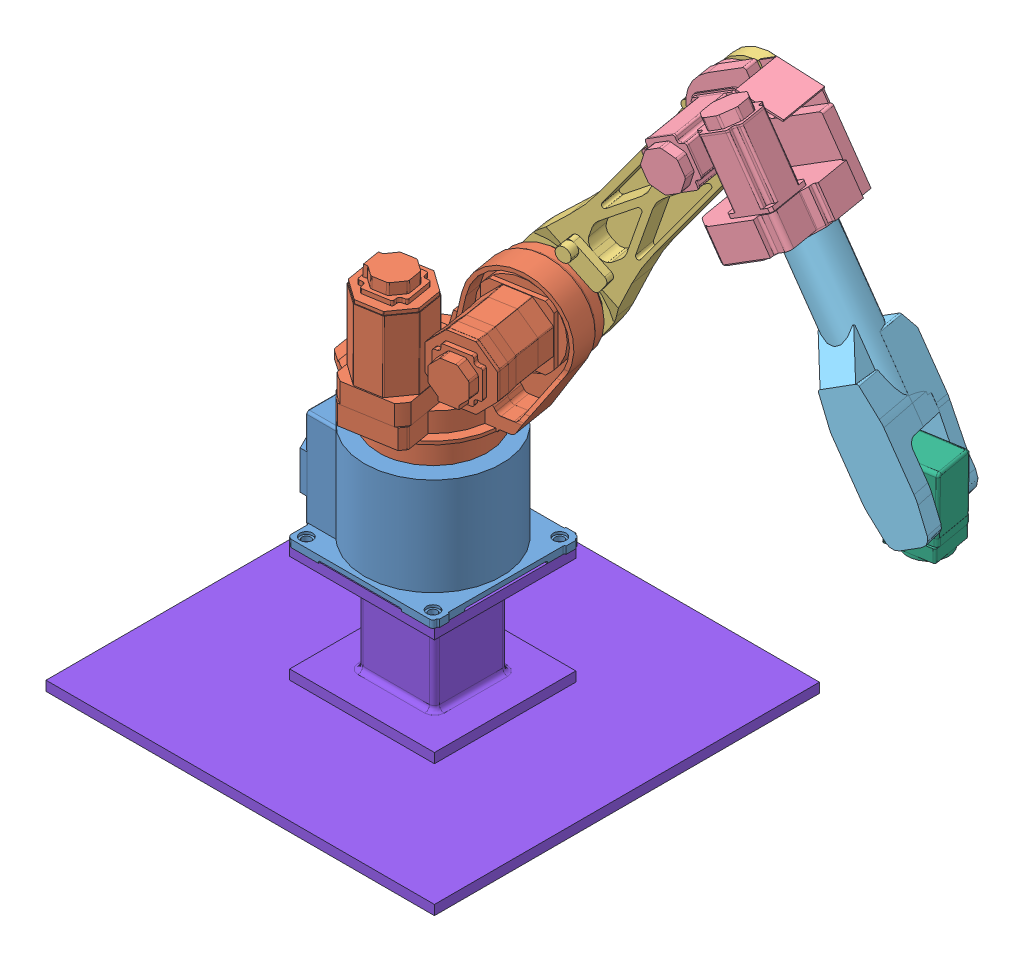
SolidWorks assembly M6iB, configuration Zero Position. Lengths in mm.
Overall size (1349.13 1360.02 790.07).
9 component instances, 9 part files, 26 mates.
Components (placement in the parent):
- M6iB base-1: M6iB base [Default] at origin size (344.77 275.74 303)
- M6iB axis1-1: M6iB axis1 [Default] at (0 214.8205 0) x (0.98613 0 -0.165974) z (0.165974 0 0.98613) size (392 336 312.77)
- M6iB axis2-1: M6iB axis2 [Default] at (124.5596 449.8205 -163.687) x (0.803965 -0.579077 -0.135314) z (0.165974 0 0.98613) size (178 760 136.26)
- M6iB axis3-1: M6iB axis3 [Default] at (490.5467 938.984 -82.5632) x (0.478263 -0.87452 -0.080496) z (0.165974 0 0.98613) size (231.49 270.86 227.8)
- M6iB axis4-1: M6iB axis4 [Default] at (651.0305 851.7238 -109.574) x (0.478263 -0.87452 -0.080496) z (0.177061 0.006243 0.98418) size (506.35 104.71 152.08)
- M6iB axis5-1: M6iB axis5 [Default] at (870.3182 450.7565 -146.4581) x (-0.011041 -0.999904 0.008329) z (0.177061 0.006243 0.98418) size (163.58 96.4 86.39)
- M6iB axis6-1: M6iB axis6 [Default] at (869.2132 350.6814 -145.6245) x (-0.177525 0.010157 0.984064) z (-0.011041 -0.999904 0.008329) size (73 73 12.5)
- BasePavimento-1: BasePavimento [Default] x (1 0 0) z (0 -1 0) size (797.07 790.07 260)
- Mesa-1: Mesa [Default] at (0 -260 0) x (1 0 0) z (0 -1 0)
Mates (geometry in assembly coordinates):
- Axis1 Angle1: planar angle = 0 rad anti-aligned: plane of M6iB base-1 through (0 0 0) normal (0 0 1); plane of ? through (0 214.8205 0) normal (0 0 1)
- Axis2 Angle2: unknown = 0 mm anti-aligned: unknown of ?; unknown of ?
- Axis3 Angle3: unknown = 0 mm anti-aligned: unknown of ?; unknown of ?
- Axis4 Angle4: unknown = 0 mm anti-aligned: unknown of ?; unknown of ?
- Axis5 Angle5: unknown = 0 mm anti-aligned: unknown of ?; unknown of ?
- Axis6 Angle6: unknown = 0 mm aligned: unknown of ?; unknown of ?
- Coincident1: coincident aligned: axis of M6iB base-1; axis of M6iB axis1-1
- Distance1: distance = 0.254 mm anti-aligned: plane of M6iB base-1 through (0 215.0745 0) normal (0 1 0); plane of M6iB axis1-1 through (0 214.8205 0) normal (0 -1 0)
- Coincident2: coincident aligned: axis of M6iB axis1-1; axis of M6iB axis2-1
- Distance2: distance = 0.254 mm anti-aligned: plane of M6iB axis1-1 through (132.4526 449.8205 -116.7906) normal (-0.165974 0 -0.98613); plane of M6iB axis2-1 through (132.4948 449.8205 -116.5401) normal (0.165974 0 0.98613)
- Coincident3: coincident anti-aligned: axis of M6iB axis2-1; axis of M6iB axis3-1
- Distance3: distance = 0.0254 mm anti-aligned: plane of M6iB axis2-1 through (475.9708 938.984 -169.1656) normal (0.165974 0 0.98613); plane of M6iB axis3-1 through (475.975 938.984 -169.1406) normal (-0.165974 0 -0.98613)
- Coincident4: coincident anti-aligned: axis of M6iB axis3-1; axis of M6iB axis4-1
- Distance4: distance = 0.254 mm anti-aligned: plane of M6iB axis3-1 through (712.7886 889.7003 -158.3796) normal (0.478263 -0.87452 -0.080496); plane of M6iB axis4-1 through (651.0305 851.7238 -109.574) normal (-0.478263 0.87452 0.080496)
- Coincident5: coincident aligned: axis of M6iB axis4-1; axis of M6iB axis5-1
- Distance5: distance = 0.889 mm anti-aligned: plane of M6iB axis4-1 through (780.7697 501.1049 -89.5399) normal (-0.177061 -0.006243 -0.98418); plane of M6iB axis5-1 through (877.3276 451.0037 -107.4969) normal (0.177061 0.006243 0.98418)
- Coincident6: coincident anti-aligned: plane of M6iB axis5-1 through (869.3512 363.1802 -145.7286) normal (-0.011041 -0.999904 0.008329); plane of M6iB axis6-1 through (869.3512 363.1802 -145.7286) normal (0.011041 0.999904 -0.008329)
- Concentric1: concentric anti-aligned: cylinder of M6iB axis5-1; cylinder of M6iB axis6-1
- InPlace1: in place: moOrthogonalPlaneRef_w of M6iB base-1; unknown of BasePavimento-1
- Coincident7: coincident aligned: plane of ?; plane of ?
- Coincident8: coincident aligned: moOrthogonalPlaneRef_w of ?; plane of ?
- Coincident9: coincident anti-aligned: moOrthogonalPlaneRef_w of ?; plane of ?
- InPlace2: in place: unknown of BasePavimento-1; unknown of Mesa-1
- Coincident10: coincident aligned: plane of ?; plane of ?
- Coincident11: coincident aligned: moOrthogonalPlaneRef_w of ?; plane of ?
- Coincident12: coincident anti-aligned: moOrthogonalPlaneRef_w of ?; plane of ?
